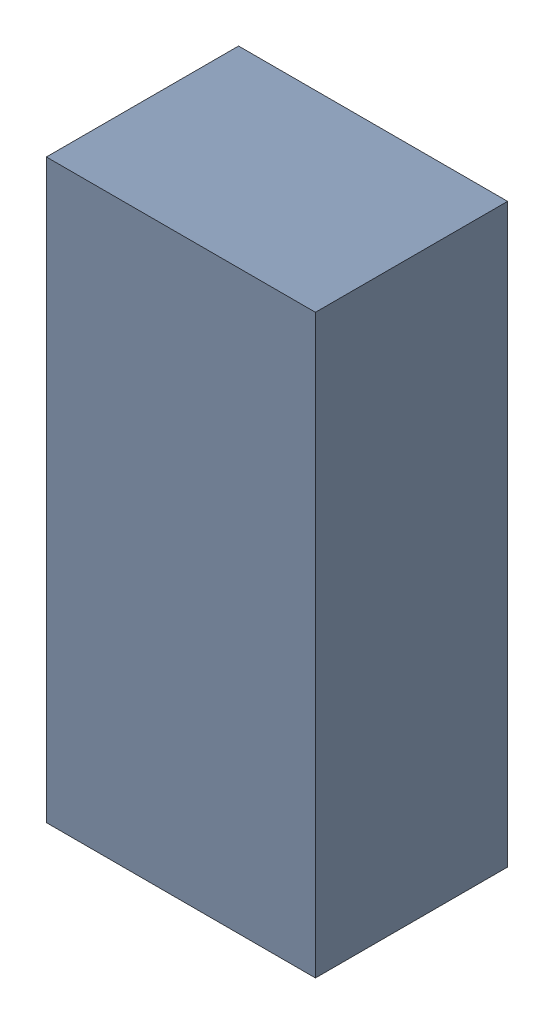
SolidWorks assembly Q3-2, configuration Default. Lengths in mm.
Overall size (1.4 3 1).
2 component instances, 1 part files, 0 mates.
Components (placement in the parent):
- 959206624-2-1: 959206624-2 [Default] at (105.664 90.805 0.1) size (1.4 3 1)
  - Extruded-72-1: Extruded-72 [Default] at origin size (1.4 3 1)
